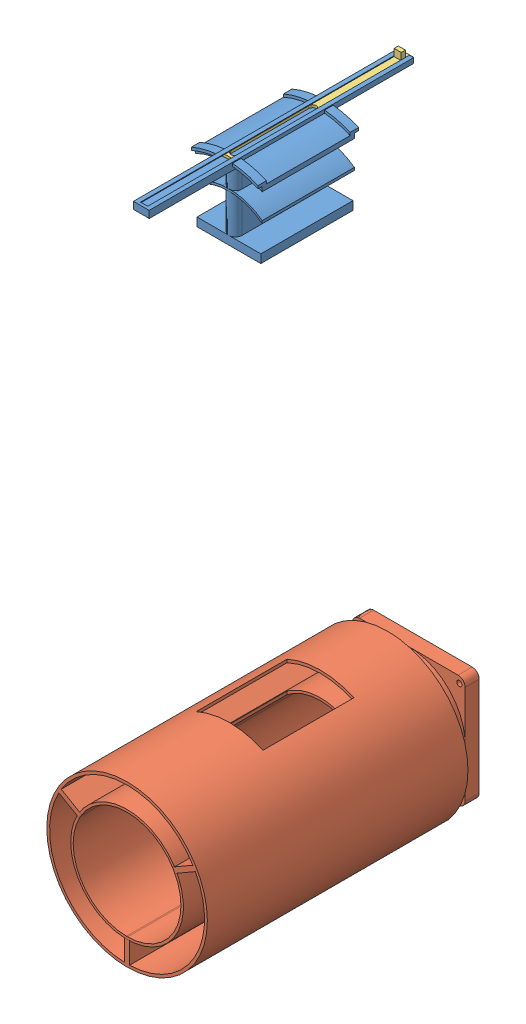
SolidWorks assembly Shell Assambled, configuration Default. Lengths in mm.
Overall size (114 467.47 210).
3 component instances, 3 part files, 7 mates.
Components (placement in the parent):
- Drawer-1: Drawer [Default] at (0 353.6848 100) x (-1 0 0) z (0 -1 0) size (47.3 187.8 55.29)
- Shell Sensors-1: Shell Sensors [KA8038HA] at origin size (114 114 210)
- CoverCable-1: CoverCable [Default] at (0 404.4725 40.8783) x (1 0 0) z (0 1 0) size (9.4 126.7 7.02)
Mates (geometry in assembly coordinates):
- Coincident1: coincident aligned: plane of Shell Sensors-1 through (0 0 0) normal (0 0 1)
- Coincident2: coincident aligned: plane of Shell Sensors-1 through (0 0 0) normal (0 1 0)
- Coincident3: coincident aligned: plane of Shell Sensors-1 through (0 0 0) normal (1 0 0)
- Coincident8: coincident anti-aligned: plane of Drawer-1 through (0 353.6848 100) normal (-1 0 0)
- Coincident9: coincident anti-aligned: plane of Drawer-1 through (0 353.6848 100) normal (0 0 -1)
- Coincident10: coincident anti-aligned: plane of Drawer-1 through (0 353.6848 100) normal (-1 0 0); plane of CoverCable-1 through (0 404.4725 40.8783) normal (1 0 0)
- Coincident11: coincident anti-aligned: plane of Drawer-1 through (0 405.4725 7.1) normal (0 -1 0); plane of CoverCable-1 through (0 405.4725 40.8783) normal (0 1 0)
